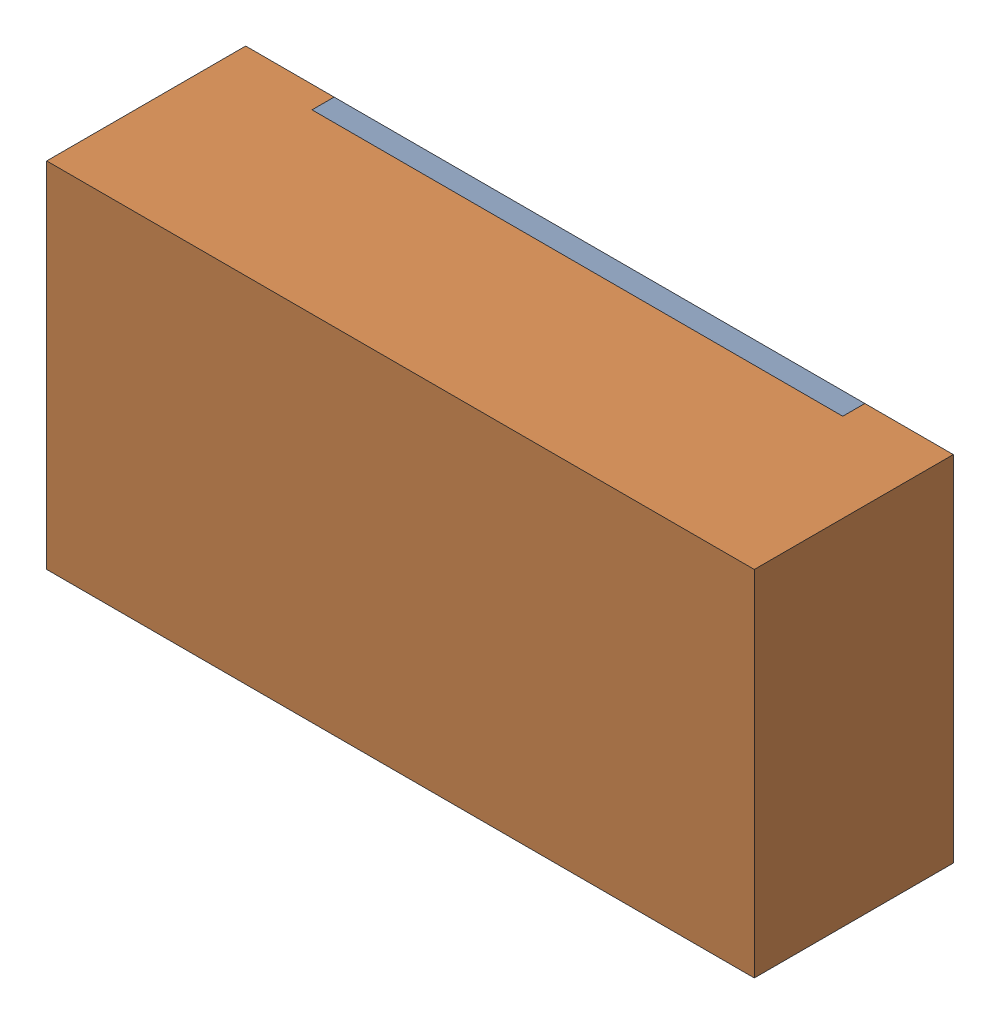
SolidWorks assembly R7, configuration 默认. Lengths in mm.
Overall size (1.6 0.8 0.45).
3 component instances, 2 part files, 0 mates.
Components (placement in the parent):
- R7-subassembly-1-1: R7-subassembly-1 [默认] at (3.6831 13.5889 -1.6914) x (1 0 0) z (0 0 -1) size (1.6 0.8 0.45)
  - R0603-1: R0603 [默认] at origin size (1.2 0.8 0.05)
  - R0603-1-1: R0603-1 [默认] at origin size (1.6 0.8 0.45)
